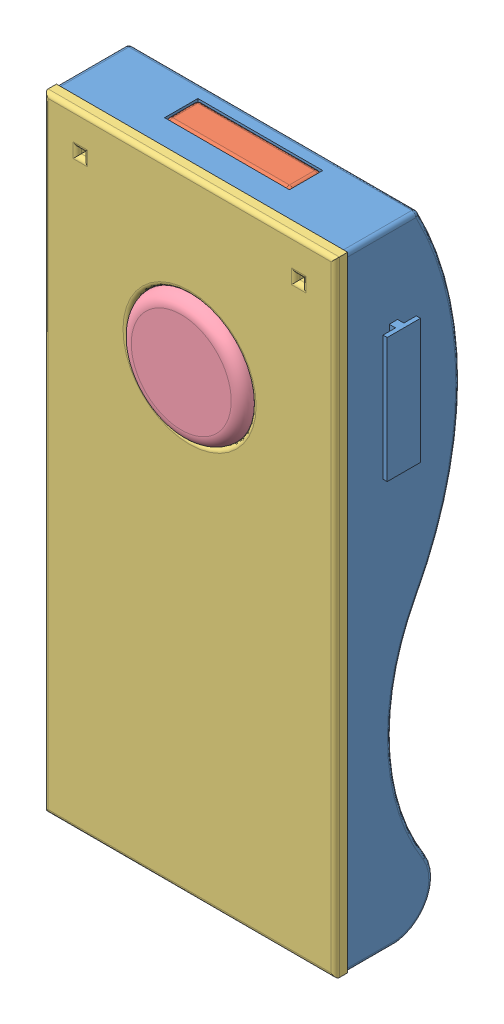
SolidWorks assembly trackerunit, configuration Default. Lengths in mm.
Overall size (75 150 32).
4 component instances, 4 part files, 6 mates.
Components (placement in the parent):
- tracker-1: tracker [Default] at origin size (75 150 27)
- tagbox-1: tagbox [Default] at (-15 40 -17) size (30 30 8)
- cover-1: cover [Default] at (0 20 -3) size (70 150 3)
- button-1: button [Default] at (0 0 -3) x (-0.752651 -0.658419 0) z (0 0 1) size (30 30 5)
Mates (geometry in assembly coordinates):
- Coincident2: coincident anti-aligned: plane of tracker-1 through (-15 10 -9) normal (0 0 -1); plane of tagbox-1 through (-15 10 -9) normal (0 0 1)
- Coincident3: coincident anti-aligned: plane of tracker-1 through (-15 10 -17) normal (1 0 0); plane of tagbox-1 through (-15 40 -9) normal (-1 0 0)
- Coincident4: coincident anti-aligned: plane of tracker-1 through (-15 10 -9) normal (0 1 0); plane of tagbox-1 through (-15 10 -9) normal (0 -1 0)
- Coincident5: coincident anti-aligned: line of tracker-1; line of cover-1
- Coincident6: coincident aligned: line of tracker-1; line of cover-1
- Coincident7: coincident anti-aligned: circle of cover-1; circle of button-1
